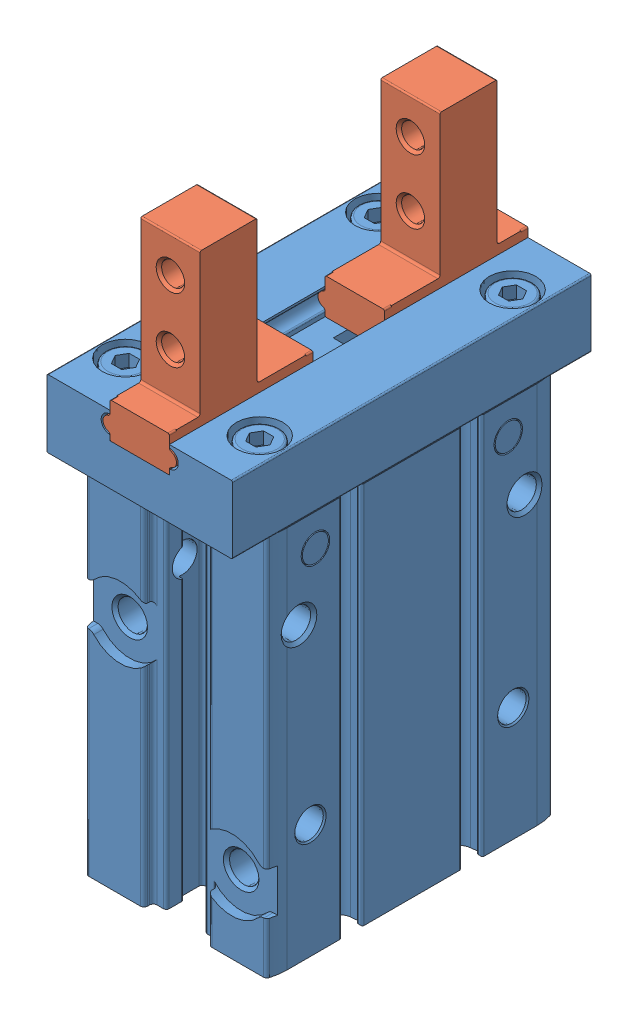
SolidWorks assembly 8116817 DHPC-20-A-S---(1high), configuration Default. Lengths in mm.
Overall size (26 84.4 50.2).
3 component instances, 2 part files, 6 mates.
Components (placement in the parent):
- 8116731 DHPC-20-A-S---(highG)-1: 8116731 DHPC-20-A-S---(highG) [Default] x (0 0 1) z (-1 0 0) size (50.2 63.1 26)
- 8111962 DHPC-20-A---(high)-1: 8111962 DHPC-20-A---(high) [Default] at (0 59.4 6) size (10.8 27 20.1)
- 8111962 DHPC-20-A---(high)-2: 8111962 DHPC-20-A---(high) [Default] at (0 59.4 -6) x (-1 0 0) z (0 0 -1) size (10.8 27 20.1)
Mates (geometry in assembly coordinates):
- LimitDistance1: limit distance = 5 mm anti-aligned: plane of 8116731 DHPC-20-A-S---(highG)-1 through (0 0 3) normal (0 0 1); plane of 8111962 DHPC-20-A---(high)-1 through (0 59.4 8) normal (0 0 -1)
- Coincident1: coincident anti-aligned: line of 8116731 DHPC-20-A-S---(highG)-1 through (0 59.4 80.9) axis (0 0 -1); line of 8111962 DHPC-20-A---(high)-1 through (0 59.4 -74.9) axis (0 0 1)
- Angle3: planar angle = 0 rad aligned: plane of 8111962 DHPC-20-A---(high)-1 through (0 59.4 6) normal (1 0 0); plane of 8116731 DHPC-20-A-S---(highG)-1 through (0 0 0) normal (1 0 0)
- LimitDistance2: limit distance = 5 mm anti-aligned: plane of 8116731 DHPC-20-A-S---(highG)-1 through (0 0 -3) normal (0 0 -1); plane of 8111962 DHPC-20-A---(high)-2 through (0 59.4 -8) normal (0 0 1)
- Coincident2: coincident anti-aligned: line of 8116731 DHPC-20-A-S---(highG)-1 through (0 59.4 -80.9) axis (0 0 1); line of 8111962 DHPC-20-A---(high)-2 through (0 59.4 74.9) axis (0 0 -1)
- Angle6: planar angle = 0 rad aligned: plane of 8111962 DHPC-20-A---(high)-2 through (0 59.4 -6) normal (-1 0 0); plane of 8116731 DHPC-20-A-S---(highG)-1 through (0 0 0) normal (-1 0 0)
